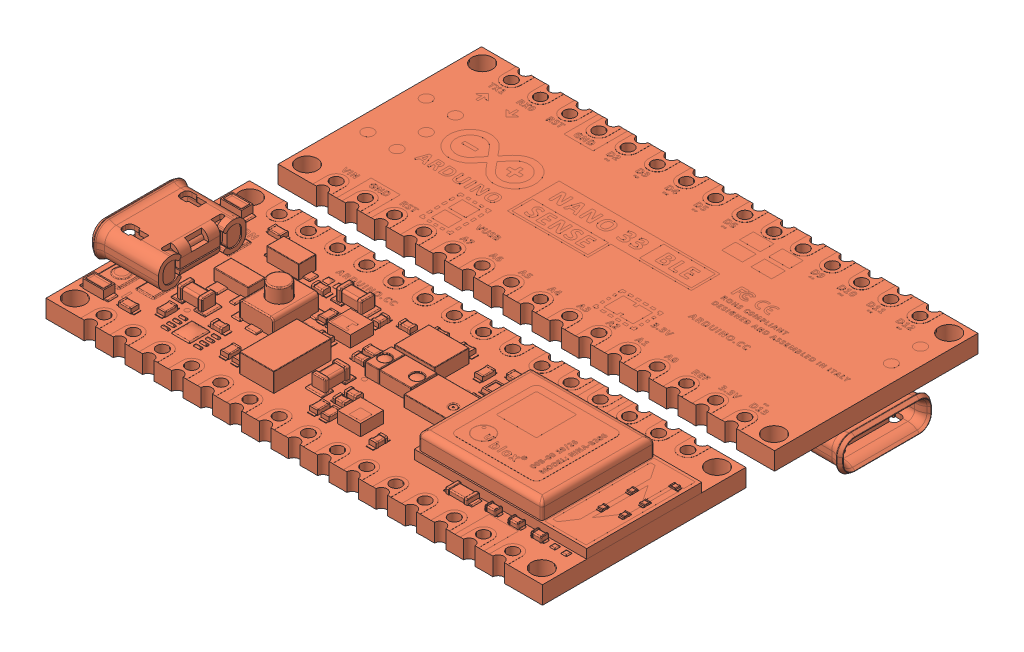
SolidWorks assembly Arduino Top Bottom NANO 33 BLE SENSE, configuration Default. Lengths in mm.
Overall size (45.1 7.05 37.9).
3 component instances, 2 part files, 6 mates.
Components (placement in the parent):
- 000 Center Rectangle-1: 000 Center Rectangle [Default] at origin size (20 1 10)
- Arduino NANO 33 SENSE BLE-1: Arduino NANO 33 SENSE BLE [Default] at (0 2.551 0) x (1 0 0) z (0 1 0) size (44.15 17.7 4.31)
- Arduino NANO 33 SENSE BLE-2: Arduino NANO 33 SENSE BLE [Default] at (0 1.001 -20.2) x (-1 0 0) z (0 -1 0) size (44.15 17.7 4.31)
Mates (geometry in assembly coordinates):
- Coincident1: coincident anti-aligned: plane of 000 Center Rectangle-1 through (0 1 0) normal (0 1 0); plane of Arduino NANO 33 SENSE BLE-1 through (0 1 0) normal (0 -1 0)
- Width1: width aligned: plane of 000 Center Rectangle-1 through (10 1 -5) normal (1 0 0); plane of Arduino NANO 33 SENSE BLE-1 through (-10 1 -5) normal (-1 0 0); plane of 000 Center Rectangle-1 through (21.6 1.001 -8.85) normal (1 0 0); plane of Arduino NANO 33 SENSE BLE-1 through (-21.6 1.001 -8.85) normal (-1 0 0)
- Width2: width aligned: plane of 000 Center Rectangle-1 through (-10 1 5) normal (0 0 1); plane of Arduino NANO 33 SENSE BLE-1 through (-10 1 -5) normal (0 0 -1); plane of 000 Center Rectangle-1 through (-21.6 1.001 8.85) normal (0 0 1); plane of Arduino NANO 33 SENSE BLE-1 through (-21.6 1.001 -8.85) normal (0 0 -1)
- Coincident2: coincident aligned: plane of Arduino NANO 33 SENSE BLE-1 through (0 2.551 0) normal (0 1 0); plane of Arduino NANO 33 SENSE BLE-2 through (0 2.551 -20.2) normal (0 1 0)
- Coincident3: coincident aligned: plane of Arduino NANO 33 SENSE BLE-1 through (-21.6 1.001 -8.85) normal (-1 0 0); plane of Arduino NANO 33 SENSE BLE-2 through (-21.6 2.551 -29.05) normal (-1 0 0)
- Distance1: distance = 2.5 mm anti-aligned: plane of Arduino NANO 33 SENSE BLE-2 through (21.6 2.551 -11.35) normal (0 0 1); plane of Arduino NANO 33 SENSE BLE-1 through (-21.6 1.001 -8.85) normal (0 0 -1)
